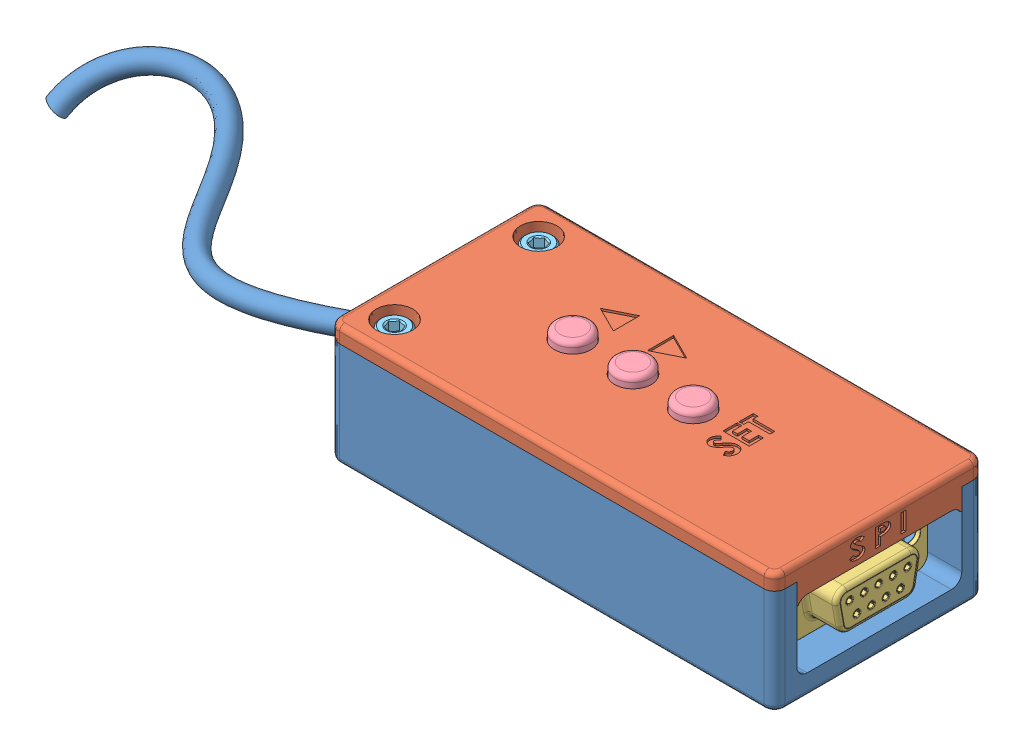
SolidWorks assembly Control_unit_assembly, configuration Default. Lengths in mm.
Overall size (183.38 38.77 53.76).
8 component instances, 5 part files, 17 mates.
Components (placement in the parent):
- ECU_case-1: ECU_case [Default] at (-29.0288 38.6921 76.0941) x (0 0 1) z (0 -1 0) size (53.76 183.38 33.77)
- ECU_cover-1: ECU_cover [Default] at (-27.3201 41.6921 54.8422) x (0 0 1) z (0 -1 0) size (40 85 10)
- D-Sub9 Female Connector with Solder Cups-1: D-Sub9 Female Connector with Solder Cups [Default] at (41.1312 29.8561 50.5591) x (-1 0 0) z (0 1 0) size (14.75 30.88 12.6)
- ECU_button-1: ECU_button [Default] at (-2.5288 37.6921 56.0941) size (8 6 8)
- ECU_button-2: ECU_button [Default] at (8.9712 37.6921 56.0941) size (8 6 8)
- ECU_button-3: ECU_button [Default] at (20.4712 37.6921 56.0941) size (8 6 8)
- M3x12_int_hex-1: M3x12_int_hex [Default] at (-22.7788 25.6921 69.8441) x (0.981295 0 0.192509) z (-0.192509 0 0.981295) size (5.5 15.04 5.5)
- M3x12_int_hex-2: M3x12_int_hex [Default] at (-22.7788 25.6921 42.3441) x (0.953075 0 0.302736) z (-0.302736 0 0.953075) size (5.5 15.04 5.5)
Mates (geometry in assembly coordinates):
- Параллельность2: parallel aligned: plane of ECU_case-1 through (-29.0288 18.6921 76.0941) normal (0 0 1); plane of Спидометр_пульт_крышка-1 through (53.9712 38.6921 76.0941) normal (0 0 1)
- Совпадение1: coincident anti-aligned: plane of ECU_case-1 through (-29.0288 38.6921 76.0941) normal (0 1 0); plane of Спидометр_пульт_крышка-1 through (53.9712 38.6921 74.0941) normal (0 -1 0)
- Концентричный1: concentric aligned: cylinder of ECU_case-1 through (53.9712 18.6921 74.0941) axis (0 1 0) radius 2; cylinder of Спидометр_пульт_крышка-1 through (53.9712 38.6921 74.0941) axis (0 1 0) radius 2
- Concentric1: concentric anti-aligned: cylinder of ECU_case-1 through (32.9712 29.0559 68.5941) axis (1 0 0) radius 1.5; cylinder of D-Sub9 Female Connector with Solder Cups-1 through (49.7712 29.0559 68.5941) axis (-1 0 0) radius 1.575
- Parallel1: parallel aligned: plane of ECU_case-1 through (48.9712 22.6921 40.3441) normal (0 1 0); plane of D-Sub9 Female Connector with Solder Cups-1 through (48.9712 34.4059 63.7491) normal (0 1 0)
- Parallel2: parallel aligned: plane of ECU_case-1 through (48.9712 22.6921 40.3441) normal (0 1 0); plane of D-Sub9 Female Connector with Solder Cups-1 through (48.9712 34.4059 63.7491) normal (0 1 0)
- Coincident3: coincident anti-aligned: plane of ECU_case-1 through (48.9712 38.6921 76.0941) normal (1 0 0); plane of D-Sub9 Female Connector with Solder Cups-1 through (48.9712 29.0559 56.0991) normal (-1 0 0)
- Concentric2: concentric aligned: cylinder of ECU_cover-1 through (-2.5288 45.6921 56.0941) axis (0 -1 0) radius 3.5; cylinder of ECU_button-1 through (-2.5288 40.6921 56.0941) axis (0 -1 0) radius 3.4
- Coincident4: coincident anti-aligned: plane of ECU_cover-1 through (53.9712 38.6921 74.0941) normal (0 -1 0); plane of ECU_button-1 through (-5.9288 38.6921 56.0941) normal (0 1 0)
- Concentric3: concentric aligned: cylinder of ECU_cover-1 through (8.9712 45.6921 56.0941) axis (0 -1 0) radius 3.5; cylinder of ECU_button-2 through (8.9712 40.6921 56.0941) axis (0 -1 0) radius 3.4
- Coincident5: coincident anti-aligned: plane of ECU_cover-1 through (53.9712 38.6921 74.0941) normal (0 -1 0); plane of ECU_button-2 through (5.5712 38.6921 56.0941) normal (0 1 0)
- Concentric4: concentric aligned: cylinder of ECU_cover-1 through (20.4712 45.6921 56.0941) axis (0 -1 0) radius 3.5; cylinder of ECU_button-3 through (20.4712 40.6921 56.0941) axis (0 -1 0) radius 3.4
- Coincident6: coincident anti-aligned: plane of ECU_cover-1 through (53.9712 38.6921 74.0941) normal (0 -1 0); plane of ECU_button-3 through (17.0712 38.6921 56.0941) normal (0 1 0)
- Concentric6: concentric anti-aligned: cylinder of ECU_cover-1 through (-22.7788 37.6921 69.8441) axis (0 1 0) radius 3.5; cylinder of M3x12_int_hex-1 through (-22.7788 25.6921 69.8441) axis (0 -1 0) radius 2.75
- Coincident8: coincident anti-aligned: plane of ECU_cover-1 through (-22.7788 37.6921 69.8441) normal (0 1 0); plane of M3x12_int_hex-1 through (-22.7788 37.6921 69.8441) normal (0 -1 0)
- Concentric7: concentric anti-aligned: cylinder of ECU_cover-1 through (-22.7788 37.6921 42.3441) axis (0 1 0) radius 3.5; cylinder of M3x12_int_hex-2 through (-22.7788 25.6921 42.3441) axis (0 -1 0) radius 2.75
- Coincident9: coincident anti-aligned: plane of ECU_cover-1 through (-22.7788 37.6921 42.3441) normal (0 1 0); plane of M3x12_int_hex-2 through (-22.7788 37.6921 42.3441) normal (0 -1 0)
